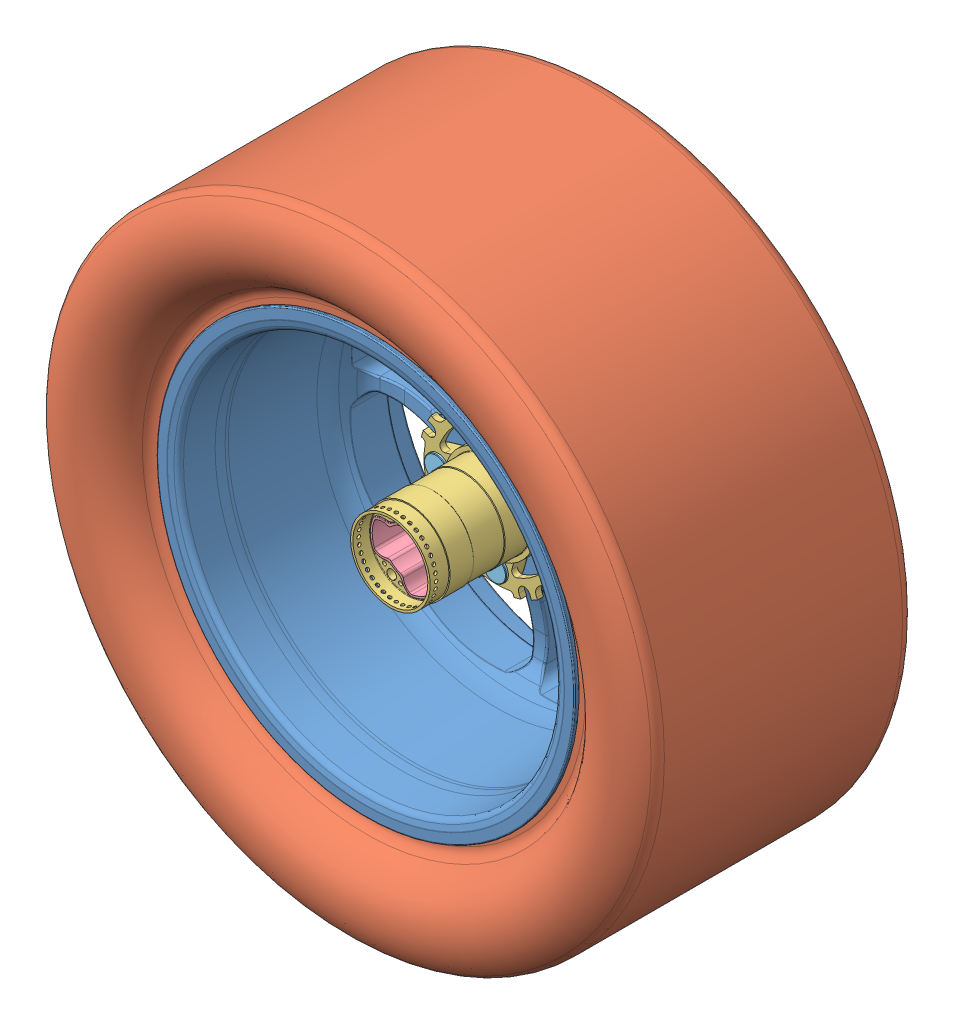
SolidWorks assembly LustroPUTM-S-SR-WT-Hub_Assembly, configuration Domyślna. Lengths in mm.
Overall size (534.5 534.5 238.76).
12 component instances, 6 part files, 0 mates.
Components (placement in the parent):
- LustroPUTM-S-WT-Wheel_Rim-1: LustroPUTM-S-WT-Wheel_Rim [Domyślna] at (27.2371 -11.0021 114.5898) x (0 0 1) z (-1 -0.000237 0) size (189.8 356.77 356.77)
- LustroPUTM-S-SR-WT-Tire-1: LustroPUTM-S-SR-WT-Tire [Default] at (27.2371 -11.0021 144.4518) x (0.999763 0.021752 0) z (-0.021752 0.999763 0) size (523.24 238.76 523.24)
- LustroPUTM-S-SR-WT-Hub-1: LustroPUTM-S-SR-WT-Hub [Domyślna] at (27.2371 -11.0021 98.5898) x (0.000237 -1 0) z (0 0 1) size (128.55 128.55 119.65)
- LustroPUTM-S-SR-WT-WH-tripod_housing_2mm-1: LustroPUTM-S-SR-WT-WH-tripod_housing_2mm [Domyślna] at (27.2371 -11.0021 197.7398) x (-0.999996 0.00292 0) z (-0.00292 -0.999996 0) size (55.96 51.5 61.23)
- LustroPUTM-S-SF-WT-WH-wheel_stud-1: LustroPUTM-S-SF-WT-WH-wheel_stud [Domyślna] at (-22.7629 -11.014 129.5898) x (0 0 -1) z (-0.77693 -0.629587 0) size (62 20 20)
- LustroPUTM-S-SF-WT-WH-wheel_stud-2: LustroPUTM-S-SF-WT-WH-wheel_stud [Domyślna] at (27.249 -61.0021 129.5898) x (0 0 -1) z (0.990977 -0.134035 0) size (62 20 20)
- LustroPUTM-S-SF-WT-WH-wheel_stud-3: LustroPUTM-S-SF-WT-WH-wheel_stud [Domyślna] at (27.2253 38.9979 129.5898) x (0 0 -1) z (0.993487 0.113947 0) size (62 20 20)
- LustroPUTM-S-SF-WT-WH-wheel_stud-4: LustroPUTM-S-SF-WT-WH-wheel_stud [Domyślna] at (77.2371 -10.9903 129.5898) x (0 0 -1) z (0.856009 0.516961 0) size (62 20 20)
- LustroPUTM-S-WT-WheelNut-1: LustroPUTM-S-WT-WheelNut [Domyślna] at (27.2253 38.9979 74.3253) x (-0.999238 -0.039031 0) z (-0.039031 0.999238 0) size (25 27 25)
- LustroPUTM-S-WT-WheelNut-2: LustroPUTM-S-WT-WheelNut [Domyślna] at (77.2371 -10.9903 74.3253) x (0.748262 0.663403 0) z (0.663403 -0.748262 0) size (25 27 25)
- LustroPUTM-S-WT-WheelNut-3: LustroPUTM-S-WT-WheelNut [Domyślna] at (27.249 -61.0021 74.3253) x (-0.999238 -0.039031 0) z (-0.039031 0.999238 0) size (25 27 25)
- LustroPUTM-S-WT-WheelNut-4: LustroPUTM-S-WT-WheelNut [Domyślna] at (-22.7629 -11.014 74.5933) x (0.864346 0.502898 0) z (0.502898 -0.864346 0) size (25 27 25)
